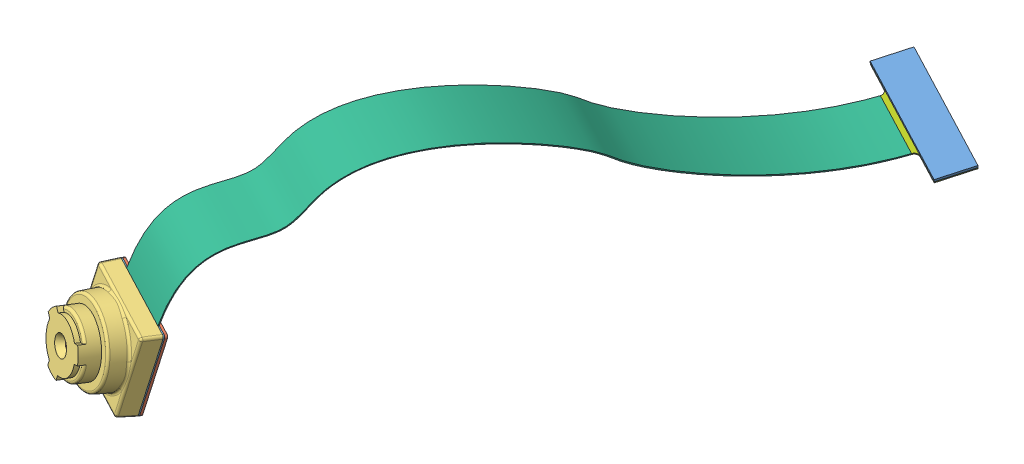
SolidWorks assembly Long-cable-ov9655, configuration Default. Lengths in mm.
Overall size (37.92 25.5 69.47).
7 component instances, 7 part files, 14 mates.
Components (placement in the parent):
- User Library-ov9655_ov9655_flex_reinf-1: User Library-ov9655_ov9655_flex_reinf [Default] at (37.3738 -2.5079 -36.4568) x (-0.902502 0.224482 -0.367557) z (0.163114 0.968004 0.190688) size (12.5 4.5 0.25)
- User Library-ov9655_ov9655_back_panel-1: User Library-ov9655_ov9655_back_panel [Default] at (17.2191 7.0431 18.7283) x (-0.902502 0.224482 -0.367557) z (-0.340779 0.149658 0.928155) size (8.5 8.5 0.25)
- User Library-ov9655_ov9655_body-1: User Library-ov9655_ov9655_body [Default] at (17.2191 7.0431 18.7283) x (-0.902502 0.224482 -0.367557) z (-0.340779 0.149658 0.928155) size (8.5 8.5 6.03)
- User Library-ov9655_ov9655_lens-1: User Library-ov9655_ov9655_lens [Default] at (17.2191 7.0431 18.7283) x (-0.902502 0.224482 -0.367557) z (-0.340779 0.149658 0.928155) size (2 2 1.43)
- flex_pcb_camera-1: flex_pcb_camera [Varsayılan] at (18.5906 -2.0396 20.6964) x (-0.902502 0.224482 -0.367557) z (-0.340779 0.149658 0.928155) size (8.5 8.5 0.12)
- flex_pcb_long_cable-1: flex_pcb_long_cable [Varsayılan] at (15.0257 -1.1529 19.2445) x (-0.902502 0.224482 -0.367557) z (0.340779 -0.149658 -0.928155) size (6.11 15.71 60.12)
- flex_pcb_pins-1: flex_pcb_pins [Varsayılan] at (44.8081 -3.4062 -38.2557) x (-0.902502 0.224482 -0.367557) z (0.163114 0.968004 0.190688) size (12.5 4 0.12)
Mates (geometry in assembly coordinates):
- Lock1: lock: unknown of User Library-ov9655_ov9655_body-1; unknown of User Library-ov9655_ov9655_lens-1
- Coincident12: coincident aligned: line of User Library-ov9655_ov9655_body-1 through (9.0908 -8.4105 18.365) axis (0.902502 -0.224482 0.367557); line of flex_pcb_camera-1 through (9.0911 -8.4106 18.3651) axis (0.902502 -0.224482 0.367557)
- Coincident13: coincident aligned: line of User Library-ov9655_ov9655_back_panel-1 through (9.132 -8.4285 18.2537) axis (0.902502 -0.224482 0.367557); line of flex_pcb_camera-1 through (9.132 -8.4285 18.2537) axis (0.902502 -0.224482 0.367557)
- Coincident14: coincident aligned: line of User Library-ov9655_ov9655_back_panel-1 through (11.0791 -0.4284 17.6787) axis (-0.263362 -0.962918 0.058568); line of flex_pcb_camera-1 through (11.0791 -0.4284 17.6787) axis (-0.263362 -0.962918 0.058568)
- Coincident15: coincident aligned: line of User Library-ov9655_ov9655_body-1 through (11.0383 -0.4101 17.79) axis (-0.263362 -0.962918 0.058568); line of flex_pcb_camera-1 through (11.0382 -0.4104 17.79) axis (-0.263362 -0.962918 0.058568)
- Coincident17: coincident anti-aligned: plane of flex_pcb_camera-1 through (18.5906 -2.0396 20.6964) normal (0.263362 0.962918 -0.058568); plane of flex_pcb_long_cable-1 through (15.0257 -1.1529 19.2445) normal (-0.263362 -0.962918 0.058568)
- Coincident18: coincident anti-aligned: line of flex_pcb_camera-1 through (18.5497 -2.0216 20.8077) axis (-0.902502 0.224482 -0.367557); line of flex_pcb_long_cable-1 through (12.2322 -0.4503 18.2348) axis (0.902502 -0.224482 0.367557)
- Distance1: distance = 1 mm: line of flex_pcb_long_cable-1 through (12.273 -0.4682 18.1235) axis (-0.340779 0.149658 0.928155); line of flex_pcb_camera-1 through (11.3705 -0.2437 17.7559) axis (-0.340779 0.149658 0.928155)
- Coincident20: coincident anti-aligned: plane of flex_pcb_long_cable-1 through (37.5731 -2.4518 -36.912) normal (0.398602 0.112142 -0.910242); plane of flex_pcb_pins-1 through (43.2137 -3.8548 -34.6147) normal (-0.398602 -0.112142 0.910242)
- Coincident21: coincident aligned: line of flex_pcb_long_cable-1 through (40.3257 -3.1365 -35.7909) axis (-0.902502 0.224482 -0.367557); line of flex_pcb_pins-1 through (40.3257 -3.1365 -35.7909) axis (-0.902502 0.224482 -0.367557)
- Coincident22: coincident aligned: line of flex_pcb_long_cable-1 through (34.8205 -1.7671 -38.033) axis (0.163114 0.968004 0.190688); line of flex_pcb_pins-1 through (34.8205 -1.7671 -38.033) axis (0.163114 0.968004 0.190688)
- Coincident24: coincident aligned: plane of User Library-ov9655_ov9655_flex_reinf-1 through (32.6496 -0.7364 -40.7792) normal (-0.902502 0.224482 -0.367557); plane of flex_pcb_pins-1 through (33.5269 -0.6002 -42.8501) normal (-0.902502 0.224482 -0.367557)
- Coincident25: coincident aligned: plane of User Library-ov9655_ov9655_flex_reinf-1 through (39.1871 -1.8871 -40.53) normal (0.398602 0.112142 -0.910242); plane of flex_pcb_pins-1 through (44.8081 -3.4062 -38.2557) normal (0.398602 0.112142 -0.910242)
- Coincident26: coincident anti-aligned: plane of User Library-ov9655_ov9655_flex_reinf-1 through (38.2902 -2.1394 -38.482) normal (-0.163114 -0.968004 -0.190688); plane of flex_pcb_pins-1 through (44.8277 -3.2901 -38.2328) normal (0.163114 0.968004 0.190688)
